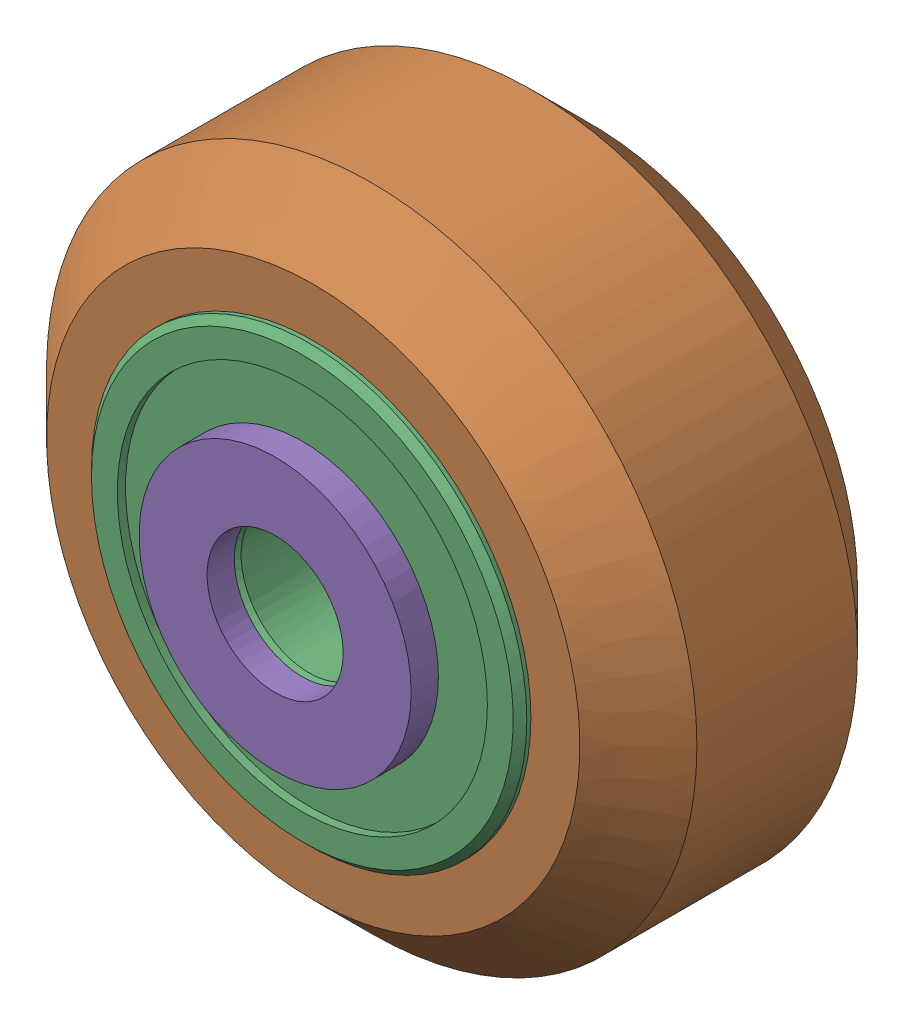
SolidWorks assembly Xtreme Solid V Wheel Kit Assembly_3, configuration Default. Lengths in mm.
Overall size (23.9 23.9 13).
6 component instances, 3 part files, 0 mates.
Components (placement in the parent):
- Precision Shim - 10x5x1mm-1: Precision Shim - 10x5x1mm [Default] at origin size (10 10 1)
- Xtreme Solid V Wheel Assembly_3-1: Xtreme Solid V Wheel Assembly_3 [Default] at (154.85 25 -23.5) size (23.9 23.9 11)
  - Xtreme Solid V Wheel-1: Xtreme Solid V Wheel [Default] at (-154.85 -25 30) x (0 0 1) z (-1 0 0) size (10.2 23.9 23.9)
  - Wheel+Kit+-+5x16x5mm+Sealed+Radial+Ball+Bearing.step.f3d-1: Wheel+Kit+-+5x16x5mm+Sealed+Radial+Ball+Bearing.step.f3d [Default] at (-154.85 -25 30) x (0 1 0) z (-1 0 0) size (16 5 16)
  - Wheel+Kit+-+5x16x5mm+Sealed+Radial+Ball+Bearing.step.f3d-2: Wheel+Kit+-+5x16x5mm+Sealed+Radial+Ball+Bearing.step.f3d [Default] at (-154.85 -25 30) x (0 1 0) z (1 0 0) size (16 5 16)
- Precision Shim - 10x5x1mm-2: Precision Shim - 10x5x1mm [Default] at (0 0 12) size (10 10 1)
